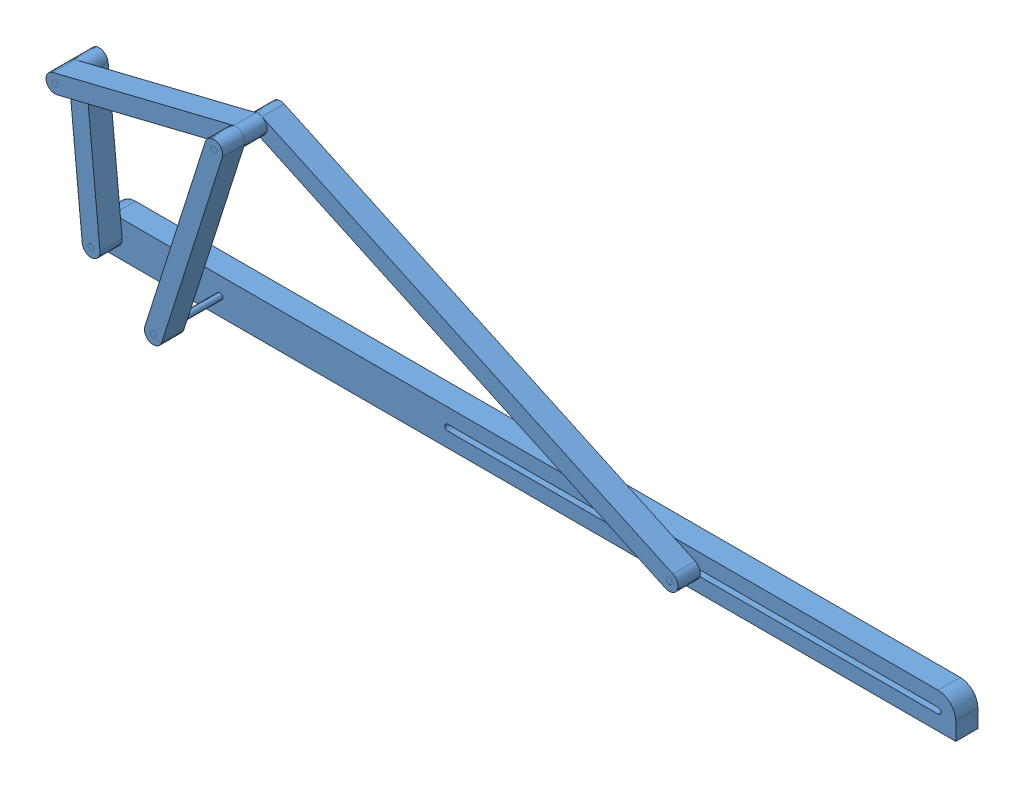
SolidWorks assembly Ensamble_Cuatro_Barras_2, configuration Default. Lengths in mm.
Overall size (209.08 49.65 20).
10 component instances, 1 part files, 16 mates.
Components (placement in the parent):
- Cuatro_Barras_2-1: Cuatro_Barras_2 [Soporte] at (-18.4727 92.1306 156.1691) size (193.7 8 5)
- Cuatro_Barras_2-2: Cuatro_Barras_2 [Eslabon A] at (-18.4727 92.1306 156.1691) x (0.814319 0.580417 0) z (0 0 1) size (20.5 32.58 5)
- Cuatro_Barras_2-3: Cuatro_Barras_2 [Eslabon B] at (-31.054 93.3558 161.1691) x (0.972792 0.231681 0) z (0 0 1) size (46 4.31 5)
- Cuatro_Barras_2-4: Cuatro_Barras_2 [Eslabon C] at (-14.7322 79.2638 166.1691) x (0.844146 0.536114 0) z (0 0 1) size (38.5 32.89 5)
- Cuatro_Barras_2-5: Cuatro_Barras_2 [Eslabon E] at (-42.9356 114.9864 156.1691) x (0.989253 -0.146211 0) z (0 0 1) size (101.82 32.89 5)
- Cuatro_Barras_2-7: Cuatro_Barras_2 [PIN2] at (9.5299 109.5907 156.1691) x (-0.88249 0.470331 0) z (0 0 1) size (1.33 1.33 10)
- Cuatro_Barras_2-11: Cuatro_Barras_2 [PIN] at (-150.7937 92.1306 161.1691) size (1.33 1.33 20)
- Cuatro_Barras_2-12: Cuatro_Barras_2 [PIN2] at (-38.1241 96.4009 161.1691) size (1.33 1.33 10)
- Cuatro_Barras_2-14: Cuatro_Barras_2 [PIN2] at (144.6728 93.5978 156.1691) x (-0.538011 0.842938 0) z (0 0 1) size (1.33 1.33 10)
- Cuatro_Barras_2-15: Cuatro_Barras_2 [PIN3] at (-39.3397 106.1227 161.1691) size (1.33 1.33 15)
Mates (geometry in assembly coordinates):
- Coincidente1: coincident: plane of Cuatro_Barras_2-1 through (-18.4727 92.1306 156.1691) normal (0 0 1); plane of Cuatro_Barras_2-2 through (-18.4727 92.1306 156.1691) normal (0 0 -1)
- Concéntrica1: concentric: circle of Cuatro_Barras_2-1; circle of Cuatro_Barras_2-2
- Concéntrica2: concentric: circle of Cuatro_Barras_2-1; circle of Cuatro_Barras_2-4
- Concéntrica3: concentric: circle of Cuatro_Barras_2-2; circle of Cuatro_Barras_2-3
- Concéntrica4: concentric: circle of Cuatro_Barras_2-3; circle of Cuatro_Barras_2-4
- Concéntrica5: concentric: circle of Cuatro_Barras_2-3; circle of Cuatro_Barras_2-5
- Concéntrica6: concentric: circle of Cuatro_Barras_2-2; circle of Cuatro_Barras_2-7
- Coincidente8: coincident: plane of Cuatro_Barras_2-2 through (-18.4727 92.1306 161.1691) normal (0 0 1); circle of Cuatro_Barras_2-7
- Coincidente12: coincident: plane of Cuatro_Barras_2-3 through (-21.6241 124.9798 166.1691) normal (0 0 1); plane of Cuatro_Barras_2-4 through (5.5273 92.1306 166.1691) normal (0 0 -1)
- Coincidente13: coincident: plane of Cuatro_Barras_2-3 through (-21.6241 124.9798 161.1691) normal (0 0 -1); plane of Cuatro_Barras_2-5 through (19.1591 135.0162 161.1691) normal (0 0 1)
- Coincidente14: coincident: plane of Cuatro_Barras_2-2 through (-18.4727 92.1306 161.1691) normal (0 0 1); plane of Cuatro_Barras_2-3 through (-21.6241 124.9798 161.1691) normal (0 0 -1)
- Coincidente15: coincident: circle of Cuatro_Barras_2-4; circle of Cuatro_Barras_2-11
- Coincidente16: coincident: circle of Cuatro_Barras_2-3; circle of Cuatro_Barras_2-12
- Coincidente17: coincident: circle of Cuatro_Barras_2-5; circle of Cuatro_Barras_2-14
- Tangente2: tangent: plane of Cuatro_Barras_2-1 through (56.8273 91.4656 151.1691) normal (0 1 0); cylinder of Cuatro_Barras_2-14 through (111.7055 92.1306 151.1691) axis (0 0 1) radius 0.665
- Coincidente18: coincident: circle of Cuatro_Barras_2-4; circle of Cuatro_Barras_2-15
